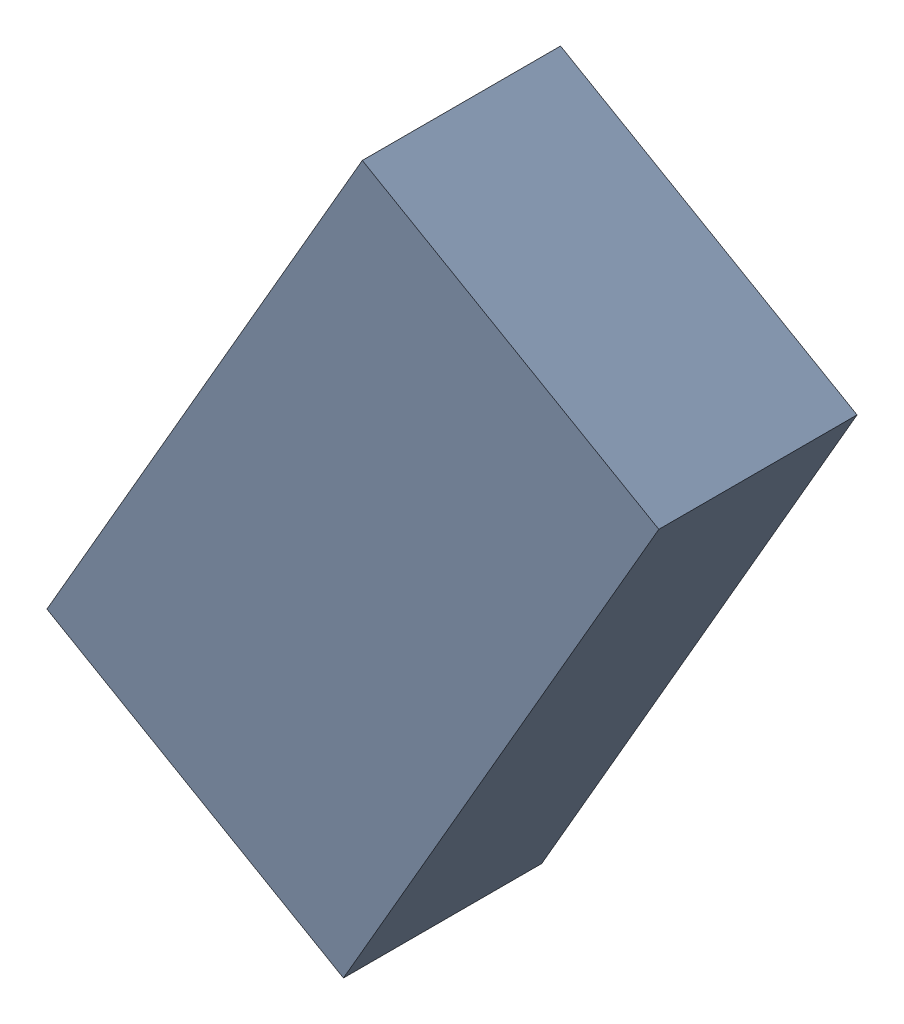
SolidWorks assembly L1_TDA6, configuration Standard. Lengths in mm.
Overall size (1.7 1.99 0.55).
2 component instances, 1 part files, 0 mates.
Components (placement in the parent):
- 885543600-1: 885543600 [Standard] at (-47.0051 30.7771 0) size (1.7 1.99 0.55)
  - Extruded_17-1: Extruded_17 [Standard] at origin size (1.7 1.99 0.55)
